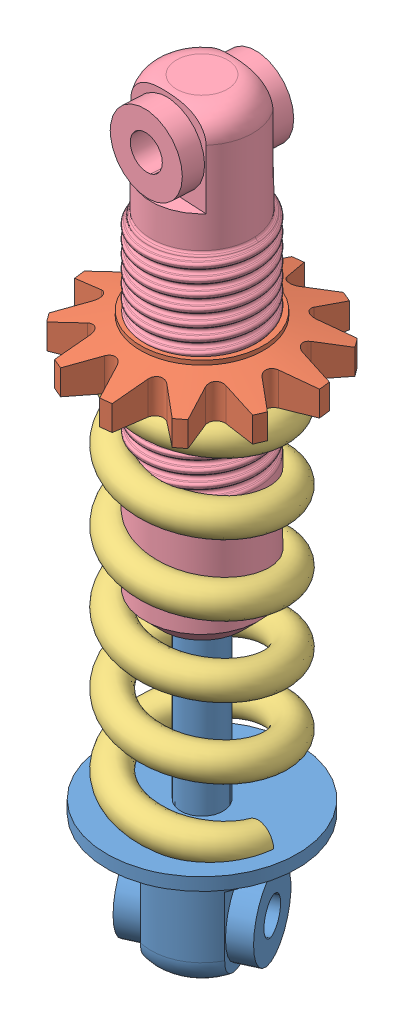
SolidWorks assembly Assem1, configuration Default. Lengths in mm.
Overall size (66.14 179.96 66.14).
4 component instances, 4 part files, 6 mates.
Components (placement in the parent):
- base-1: base [Default] at (223.0468 -97.3475 0.2109) x (0.908282 0 -0.418357) z (0.418357 0 0.908282) size (45 101.45 45)
- nut-1: nut [Default] at (223.0468 -4.4475 0.2109) x (0.927891 0 -0.372852) z (0.372852 0 0.927891) size (50.85 11.68 50.85)
- spring-1: spring [Default] at (223.0468 5.5525 0.2109) x (0.995543 0 0.094307) z (-0.094307 0 0.995543) size (39.14 101.7 37.7)
- top rod-1: top rod [Default] at (223.0468 -55.1962 0.2109) x (0.053028 0 -0.998593) z (0.998593 0 0.053028) size (27.73 109.35 27)
Mates (geometry in assembly coordinates):
- Concentric2: concentric: cylinder of ? through (223.0468 -35.5975 0.2109) axis (0 -1 0) radius 5; cylinder of top rod-1 through (223.0468 19.8038 0.2109) axis (0 -1 0) radius 5
- Coincident4: coincident: line of ? through (223.0468 -9.7789 0.2109) axis (0 -1 0); line of top rod-1 through (223.0468 24.9838 0.2109) axis (0 -1 0)
- Screw1: screw = 1: cylinder of assembly; line of assembly; cylinder of nut-1 through (223.0468 5.5525 0.2109) axis (0 -1 0) radius 14.5; axis of top rod-1 through (223.0468 24.9838 0.2109) axis (0 -1 0)
- Coincident5: coincident: line of ? through (223.0468 -35.5975 0.2109) axis (0 -1 0); line of ? through (223.0468 -5.6975 0.2109) axis (0 -1 0)
- Coincident6: coincident: plane of ? through (223.0468 -105.5975 0.2109) normal (0 1 0); plane of ? through (223.0468 -105.5975 0.2109) normal (0 -1 0)
- Coincident7: coincident: plane of ? through (223.0468 -15.6975 0.2109) normal (0 -1 0); plane of ? through (223.0468 -15.6975 0.2109) normal (0 1 0)
